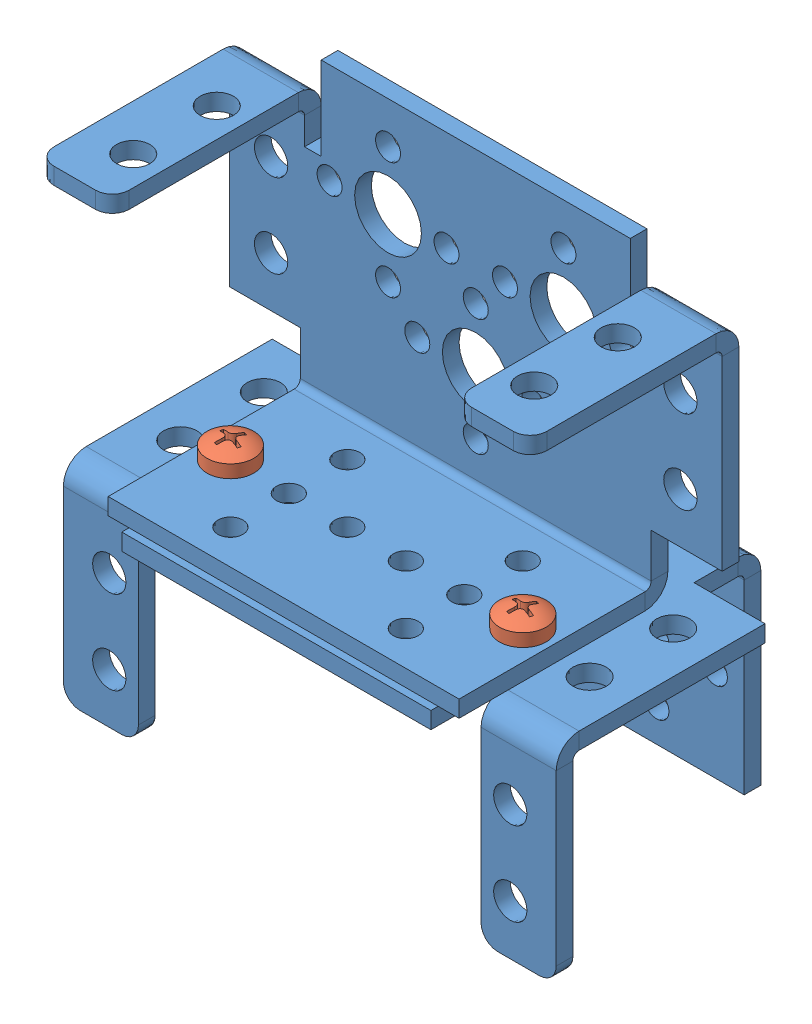
SolidWorks assembly 装配体13, configuration 默认. Lengths in mm.
Overall size (59 62 37).
6 component instances, 3 part files, 14 mates.
Components (placement in the parent):
- 多功能支架-1: 多功能支架 [默认] at (0 33 13.1317) size (59 37 25)
- 多功能支架-2: 多功能支架 [默认] at (0 -2 33) x (1 0 0) z (0 -1 0) size (59 37 25)
- GB818-M3X6-ZN-4.8-1: GB818-M3X6-ZN-4.8 [Default] at (47 -4 25) x (-0.967239 0 -0.253869) z (0 1 0) size (5.6 5.6 8.4)
- GB6170-M3-ZN-10-1: GB6170-M3-ZN-10 [Default] at (12 -2 25) x (-0.967239 0 -0.253869) z (0 1 0) size (5.5 6.35 2.4)
- GB818-M3X6-ZN-4.8-2: GB818-M3X6-ZN-4.8 [Default] at (12 -4 25) x (-0.967239 0 -0.253869) z (0 1 0) size (5.6 5.6 8.4)
- GB6170-M3-ZN-10-2: GB6170-M3-ZN-10 [Default] at (47 -2 25) x (-0.967239 0 -0.253869) z (0 1 0) size (5.5 6.35 2.4)
Mates (geometry in assembly coordinates):
- 重合1: coincident anti-aligned: plane of 多功能支架-1 through (-8.7203 1.1845 13.9692) normal (0 -1 0); plane of 多功能支架-2 through (-8.1501 0 33) normal (0 1 0)
- 同心1: concentric aligned: cylinder of 多功能支架-1 through (3.2797 11.1845 25.8375) axis (0 -1 0) radius 1.5; cylinder of 多功能支架-2 through (3.8499 0 25) axis (0 -1 0) radius 1.5
- 同心2: concentric aligned: cylinder of 多功能支架-1 through (38.2797 11.1845 25.8375) axis (0 -1 0) radius 1.5; cylinder of 多功能支架-2 through (38.8499 0 25) axis (0 -1 0) radius 1.5
- 重合2: coincident anti-aligned: plane of 多功能支架-1 through (-8.7203 3.1845 13.9692) normal (0 1 0); plane of GB818-M3X6-ZN-4.8-2 through (3.8499 2 25) normal (0 -1 0)
- 重合3: coincident anti-aligned: plane of 多功能支架-1 through (-8.7203 3.1845 13.9692) normal (0 1 0); plane of GB818-M3X6-ZN-4.8-1 through (38.8499 2 25) normal (0 -1 0)
- 同心3: concentric aligned: cylinder of 多功能支架-1 through (3.2797 11.1845 25.8375) axis (0 -1 0) radius 1.5; cylinder of GB818-M3X6-ZN-4.8-2 through (3.8499 2 25) axis (0 -1 0) radius 1.5
- 重合4: coincident aligned: circle of 多功能支架-1; cylinder of GB818-M3X6-ZN-4.8-1 through (38.8499 2 25) axis (0 -1 0) radius 1.5
- 重合5: coincident anti-aligned: plane of 多功能支架-2 through (-8.1501 -2 33) normal (0 -1 0); plane of GB6170-M3-ZN-10-1 through (3.0438 -2 28.0714) normal (0 1 0)
- 同心4: concentric anti-aligned: cylinder of GB6170-M3-ZN-10-1 through (3.8499 -4.4 25) axis (0 1 0) radius 1.25; cylinder of GB818-M3X6-ZN-4.8-2 through (3.8499 2 25) axis (0 -1 0) radius 1.5
- 重合7: coincident anti-aligned: plane of 多功能支架-2 through (-8.1501 -2 33) normal (0 -1 0); plane of GB6170-M3-ZN-10-2 through (38.0438 -2 28.0714) normal (0 1 0)
- 同心6: concentric anti-aligned: cylinder of GB818-M3X6-ZN-4.8-1 through (38.8499 2 25) axis (0 -1 0) radius 1.5; cylinder of GB6170-M3-ZN-10-2 through (38.8499 -4.4 25) axis (0 1 0) radius 1.25
- 重合8: coincident anti-aligned: plane of 多功能支架-2 through (-8.1501 -2 0) normal (0 0 -1)
- 重合9: coincident aligned: plane of 多功能支架-2 through (-8.1501 0 33) normal (0 1 0)
- 重合10: coincident anti-aligned: plane of 多功能支架-1 through (0 33 11.1317) normal (-1 0 0)
